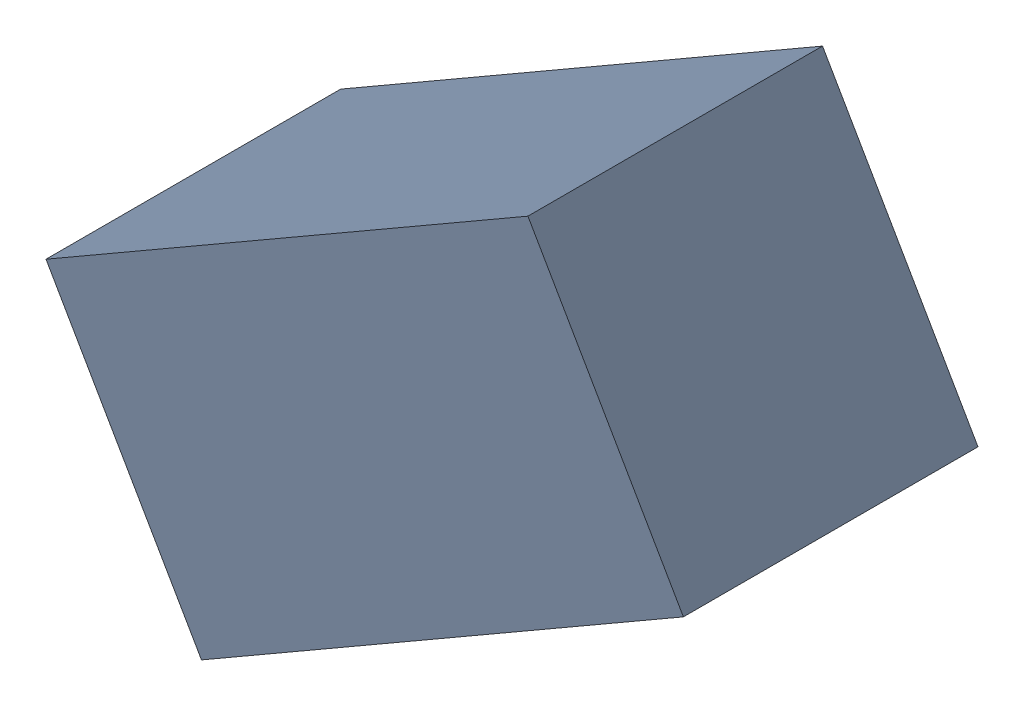
SolidWorks assembly R1_TDA5, configuration Standard. Lengths in mm.
Overall size (1.95 1.67 0.9).
2 component instances, 1 part files, 0 mates.
Components (placement in the parent):
- 885544008-1: 885544008 [Standard] at (-38.8324 -32.5162 0) size (1.95 1.67 0.9)
  - Extruded_15-1: Extruded_15 [Standard] at origin size (1.95 1.67 0.9)
